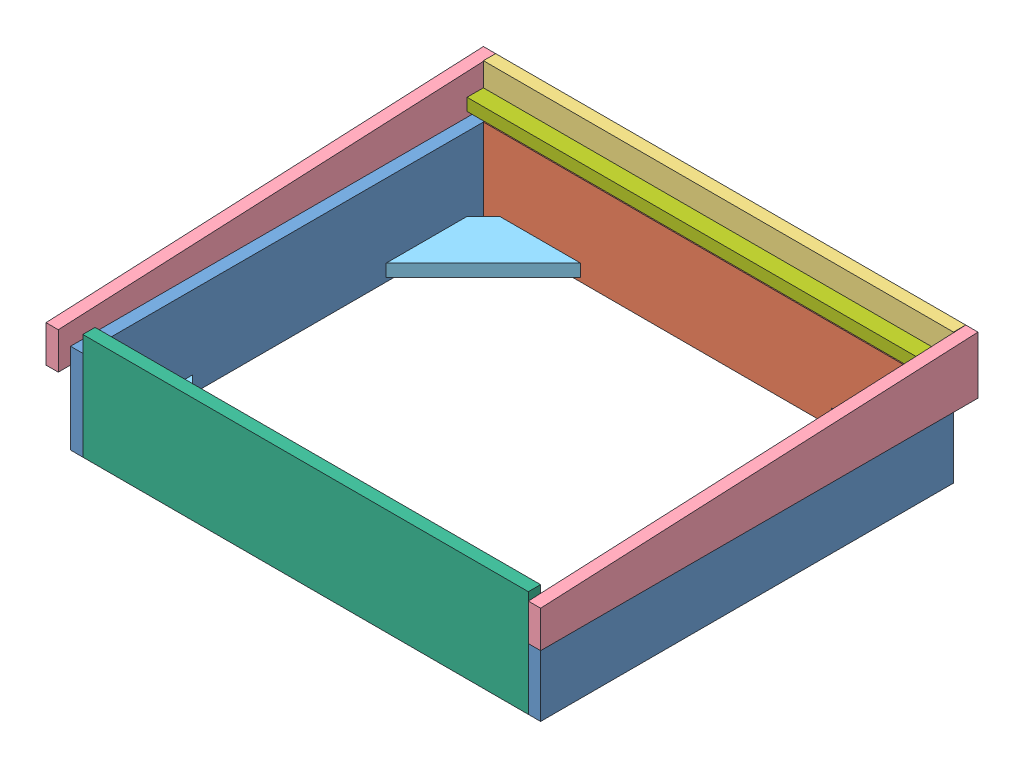
SolidWorks assembly 140117_PinHead_1, configuration Default. Lengths in mm.
Overall size (817.87 203.2 728.97).
12 component instances, 7 part files, 28 mates.
Components (placement in the parent):
- pINhEAD1-1: pINhEAD1 [Default] at (-0.8374 20.8217 297.8595) size (19.05 139.7 641.35)
- pINhEAD2-1: pINhEAD2 [Default] at (-644.4713 -46.9571 -328.932) x (0 0 1) z (-1 0 0) size (19.05 139.7 692.15)
- pINhEAD1-2: pINhEAD1 [Default] at (-712.0374 20.8217 297.8595) size (19.05 139.7 641.35)
- pINhEAD4-1: pINhEAD4 [Default] at (-15.3959 135.1217 -347.982) x (0 0 -1) z (1 0 0) size (19.05 88.9 730.25)
- pINhEAD3-1: pINhEAD3 [Default] at (-0.8374 92.1658 265.1196) size (19.05 88.9 679.45)
- pINhEAD3-2: pINhEAD3 [Default] at (-750.1374 92.1658 265.1196) size (19.05 88.9 679.45)
- pINhEAD5-1: pINhEAD5 [Default] at (-751.5724 -24.2478 -218.8861) x (0 1 0) z (-0.707107 0 0.707107) size (19.05 88.9 213.72)
- pINhEAD5-2: pINhEAD5 [Default] at (19.6476 -43.2978 -218.8861) x (0 -1 0) z (0.707107 0 0.707107) size (19.05 88.9 213.72)
- pINhEAD5-3: pINhEAD5 [Default] at (-621.0416 -24.2478 332.9031) x (0 1 0) z (0.707107 0 0.707107) size (19.05 88.9 213.72)
- pINhEAD5-4: pINhEAD5 [Default] at (19.6476 -24.2478 202.3722) x (0 1 0) z (0.707107 0 -0.707107) size (19.05 88.9 213.72)
- pINhEAD6-1: pINhEAD6 [Default] at (-87.4536 -46.9571 312.418) x (0 0 -1) z (1 0 0) size (19.05 165.1 692.15)
- pINhEAD7-1: pINhEAD7 [Default] at (-15.3959 117.0397 -258.4624) x (0 1 0) z (1 0 0) size (19.05 25.4 730.25)
Mates (geometry in assembly coordinates):
- Coincident4: coincident anti-aligned: plane of pINhEAD1-1 through (-19.8874 -49.6478 312.418) normal (-1 0 0); plane of pINhEAD2-1 through (-19.8874 90.0522 -309.882) normal (1 0 0)
- Coincident5: coincident aligned: plane of pINhEAD1-1 through (-19.8874 90.0522 312.418) normal (0 1 0); plane of pINhEAD2-1 through (-712.0374 90.0522 -309.882) normal (0 1 0)
- Coincident6: coincident aligned: plane of pINhEAD1-1 through (-19.8874 90.0522 -328.932) normal (0 0 -1); plane of pINhEAD2-1 through (-712.0374 -49.6478 -328.932) normal (0 0 -1)
- Coincident7: coincident anti-aligned: plane of pINhEAD2-1 through (-712.0374 90.0522 -309.882) normal (-1 0 0); plane of pINhEAD1-2 through (-712.0374 -49.6478 312.418) normal (1 0 0)
- Coincident8: coincident aligned: plane of pINhEAD2-1 through (-712.0374 90.0522 -309.882) normal (0 1 0); plane of pINhEAD1-2 through (-731.0874 90.0522 312.418) normal (0 1 0)
- Coincident9: coincident aligned: plane of pINhEAD2-1 through (-712.0374 -49.6478 -328.932) normal (0 0 -1); plane of pINhEAD1-2 through (-731.0874 90.0522 -328.932) normal (0 0 -1)
- Coincident13: coincident anti-aligned: plane of pINhEAD2-1 through (-712.0374 -49.6478 -328.932) normal (0 0 -1); plane of pINhEAD4-1 through (-0.8374 64.6522 -328.932) normal (0 0 1)
- Coincident14: coincident aligned: plane of pINhEAD1-1 through (-0.8374 -49.6478 312.418) normal (1 0 0); plane of pINhEAD4-1 through (-0.8374 153.5522 -328.932) normal (1 0 0)
- Distance2: distance = 114.3 mm aligned: plane of pINhEAD2-1 through (-712.0374 -49.6478 -309.882) normal (0 -1 0); plane of pINhEAD4-1 through (-0.8374 64.6522 -328.932) normal (0 -1 0)
- Coincident18: coincident aligned: plane of pINhEAD4-1 through (-0.8374 64.6522 -347.982) normal (0 0 -1); plane of pINhEAD3-1 through (18.2126 153.5522 -347.982) normal (0 0 -1)
- Coincident19: coincident aligned: plane of pINhEAD4-1 through (-0.8374 64.6522 -328.932) normal (0 -1 0); plane of pINhEAD3-1 through (18.2126 64.6522 331.468) normal (0 -1 0)
- Coincident20: coincident anti-aligned: plane of pINhEAD4-1 through (-731.0874 153.5522 -328.932) normal (-1 0 0); plane of pINhEAD3-2 through (-731.0874 64.6522 331.468) normal (1 0 0)
- Coincident21: coincident aligned: plane of pINhEAD4-1 through (-0.8374 64.6522 -347.982) normal (0 0 -1); plane of pINhEAD3-2 through (-731.0874 153.5522 -347.982) normal (0 0 -1)
- Coincident22: coincident aligned: plane of pINhEAD4-1 through (-0.8374 64.6522 -328.932) normal (0 -1 0); plane of pINhEAD3-2 through (-731.0874 64.6522 331.468) normal (0 -1 0)
- Coincident23: coincident anti-aligned: plane of pINhEAD1-2 through (-712.0374 -49.6478 312.418) normal (1 0 0); plane of pINhEAD5-1 through (-712.0374 -43.2978 -284.4858) normal (-1 0 0)
- Coincident24: coincident anti-aligned: plane of pINhEAD2-1 through (-712.0374 -49.6478 -309.882) normal (0 0 1); plane of pINhEAD5-1 through (-686.6412 -43.2978 -309.882) normal (0 0 -1)
- Distance3: distance = 6.35 mm aligned: plane of pINhEAD2-1 through (-712.0374 -49.6478 -309.882) normal (0 -1 0); plane of pINhEAD5-1 through (-712.0374 -43.2978 -309.882) normal (0 -1 0)
- Coincident27: coincident anti-aligned: plane of pINhEAD1-1 through (-19.8874 -49.6478 312.418) normal (-1 0 0); plane of pINhEAD5-2 through (-19.8874 -24.2478 -284.4858) normal (1 0 0)
- Coincident28: coincident anti-aligned: plane of pINhEAD2-1 through (-712.0374 -49.6478 -309.882) normal (0 0 1); plane of pINhEAD5-2 through (-45.2836 -24.2478 -309.882) normal (0 0 -1)
- Distance4: distance = 6.35 mm aligned: plane of pINhEAD2-1 through (-712.0374 -49.6478 -309.882) normal (0 -1 0); plane of pINhEAD5-2 through (-19.8874 -43.2978 -309.882) normal (0 -1 0)
- Coincident30: coincident anti-aligned: plane of pINhEAD1-2 through (-712.0374 -49.6478 312.418) normal (1 0 0); plane of pINhEAD5-3 through (-712.0374 -43.2978 267.9719) normal (-1 0 0)
- Coincident34: coincident anti-aligned: plane of pINhEAD1-1 through (-19.8874 -49.6478 312.418) normal (-1 0 0); plane of pINhEAD5-4 through (-19.8874 -43.2978 267.9719) normal (1 0 0)
- Coincident37: coincident anti-aligned: plane of pINhEAD1-1 through (-19.8874 -49.6478 312.418) normal (-1 0 0); plane of pINhEAD6-1 through (-19.8874 115.4522 293.368) normal (1 0 0)
- Coincident38: coincident aligned: plane of pINhEAD1-1 through (-19.8874 -49.6478 312.418) normal (0 -1 0); plane of pINhEAD6-1 through (-19.8874 -49.6478 293.368) normal (0 -1 0)
- Coincident39: coincident aligned: plane of pINhEAD1-1 through (-19.8874 90.0522 312.418) normal (0 0 1); plane of pINhEAD6-1 through (-19.8874 -49.6478 312.418) normal (0 0 1)
- Coincident40: coincident anti-aligned: plane of pINhEAD4-1 through (-0.8374 64.6522 -328.932) normal (0 0 1); plane of pINhEAD7-1 through (-0.8374 97.9897 -328.932) normal (0 0 -1)
- Coincident41: coincident anti-aligned: plane of pINhEAD3-1 through (-0.8374 64.6522 331.468) normal (-1 0 0); plane of pINhEAD7-1 through (-0.8374 97.9897 -303.532) normal (1 0 0)
- Distance9: distance = 7.9375 mm anti-aligned: plane of pINhEAD2-1 through (-712.0374 90.0522 -309.882) normal (0 1 0); plane of pINhEAD7-1 through (-0.8374 97.9897 -328.932) normal (0 -1 0)
